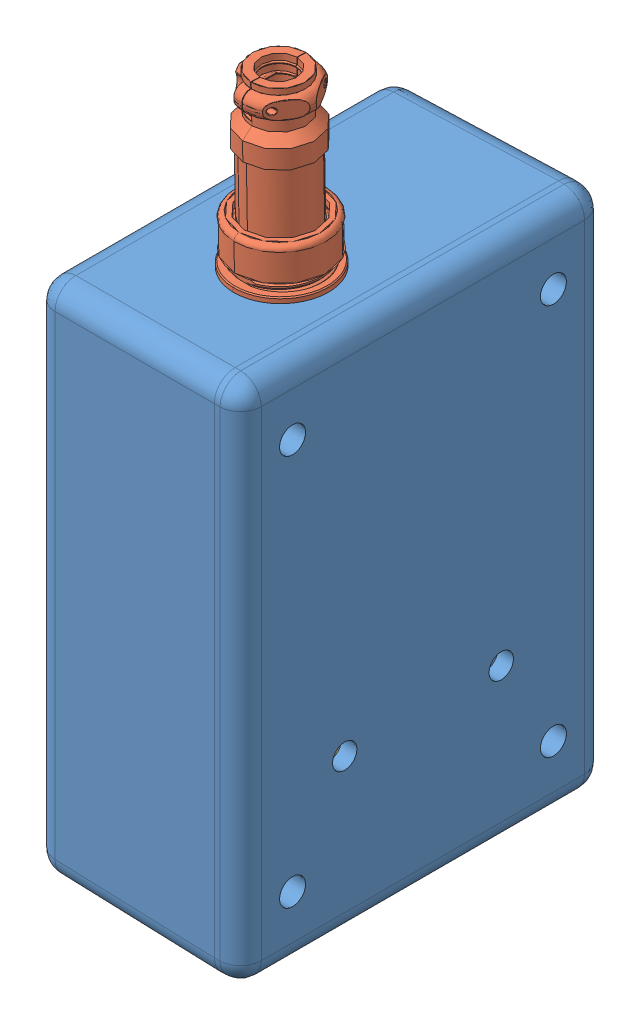
SolidWorks assembly Base_Assem, configuration Default. Lengths in mm.
Overall size (40 105.98 70).
3 component instances, 3 part files, 3 mates.
Components (placement in the parent):
- Main_Controller-1: Main_Controller [Default] at (40.9971 40.6897 82.6321) size (40 100 70)
- GX16-4P v2.step-1: GX16-4P v2.step [Default] at (27.8263 123.1648 92.1116) x (0.017452 -0.999848 0) z (0.035766 0.000624 -0.99936) size (47.5 21.45 18.91)
- MCU_PCB.step-1: MCU_PCB.step [Default] at (15.4346 -29.3104 38.205) x (0 0.999999 0.001404) z (1 0 0) size (75.68 37.85 14.81)
Mates (geometry in assembly coordinates):
- Coincident3: coincident anti-aligned: plane of Main_Controller-1 through (41.0495 87.6902 117.6321) normal (0.017452 -0.999848 0); plane of GX16-4P v2.step-1 through (28.4494 87.4702 92.1116) normal (-0.017452 0.999848 0)
- Coincident4: coincident anti-aligned: plane of Main_Controller-1 through (13.7431 -0.8203 98.6971) normal (1 0 0); plane of MCU_PCB.step-1 through (13.7431 31.2063 82.613) normal (-1 0 0)
- Coincident5: coincident aligned: circle of Main_Controller-1; circle of MCU_PCB.step-1
